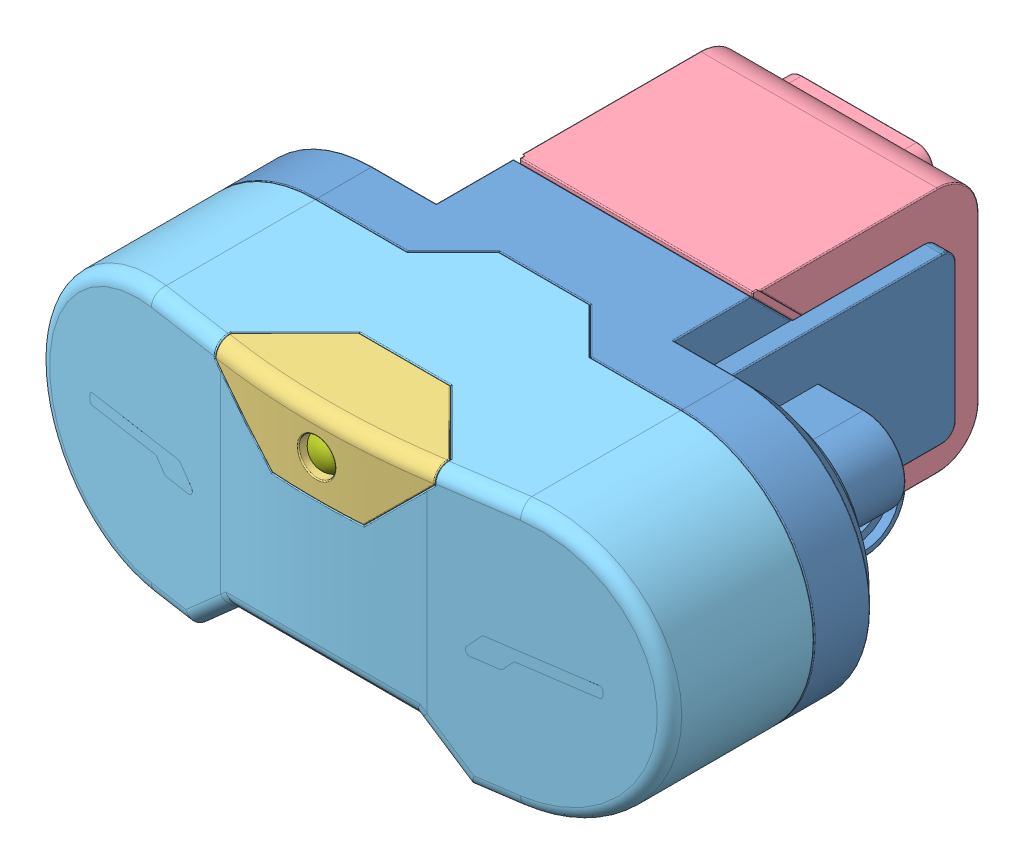
SolidWorks assembly 95654, configuration Default. Lengths in mm.
Overall size (55.41 31.24 47.82).
9 component instances, 7 part files, 0 mates.
Components (placement in the parent):
- 95654.stp-1: 95654.stp [Default] at origin size (55.41 31.24 47.82)
  - 99378-LtBluishGray.stp-1: 99378-LtBluishGray.stp [Default] at origin size (55.2 31.2 31.6)
  - 99393-LtBluishGray.stp-1: 99393-LtBluishGray.stp [Default] at (-16 0 1.2) x (-1 0 0) z (0 0 1) size (16.36 19.2 7.6)
  - 99393-LtBluishGray.stp-2: 99393-LtBluishGray.stp [Default] at (16 0 1.2) size (16.36 19.2 7.6)
  - 11016-Black.stp-1: 11016-Black.stp [Default] at (0 8.18 21.6521) size (19.45 6.88 11.76)
  - 99376-White.stp-1: 99376-White.stp [Default] at (0 0.8 -19.2) size (22.3 23.6 19.62)
  - 99392p01-TransBlackIRLens.stp-1: 99392p01-TransBlackIRLens.stp [Default] at (0 0 6.4) size (55.41 23.41 33)
  - 54732b-LtBluishGray.stp-1: 54732b-LtBluishGray.stp [Default] at (0 2.4 -25.2) x (-1 0 0) z (0 0 -1) size (12 14.56 14.4)
  - 99961-TransClear.stp-1: 99961-TransClear.stp [Default] at (0 8 21.1998) x (0 1 0) z (1 0 0) size (3.2 5.6 3.2)
